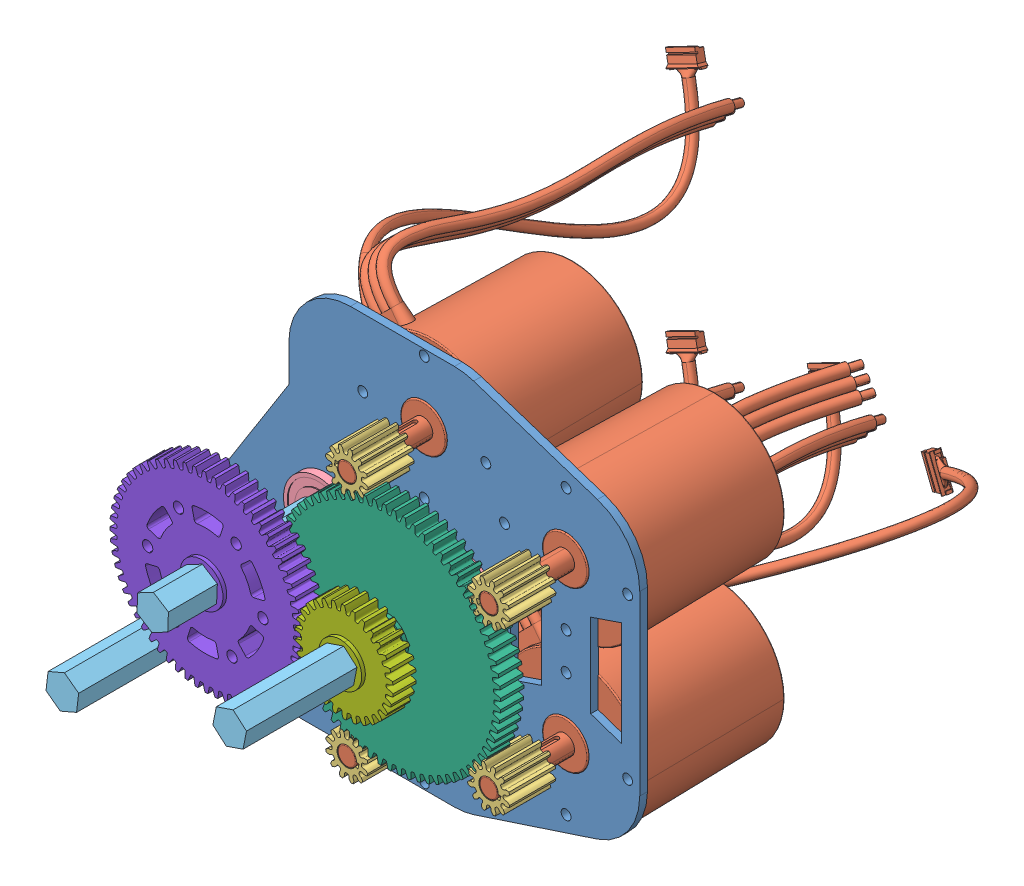
SolidWorks assembly gearbox, configuration Default. Lengths in mm.
Overall size (198.78 175.05 269.62).
20 component instances, 9 part files, 52 mates.
Components (placement in the parent):
- GearboxPlate-1: GearboxPlate [Default] at (89.3688 114.0546 160.1474) size (191.31 157.48 3.17)
- Neo-1: Neo [Default] at (131.3565 147.0746 157.1474) x (0 1 0) z (0 0 1) size (98.87 73.45 204.78)
- Neo-2: Neo [Default] at (72.8588 164.8553 157.1474) size (98.87 73.45 204.78)
- Neo-3: Neo [Default] at (72.8588 63.2539 157.1474) size (98.87 73.45 204.78)
- Neo-4: Neo [Default] at (131.3565 81.0346 157.1474) size (98.87 73.45 204.78)
- 12t_Steel_Spur_Gear_20_DP_CIM_Motor_217-3099.step-1: 12t_Steel_Spur_Gear_20_DP_CIM_Motor_217-3099.step [Default] at (131.3565 147.0746 182.6224) x (-0.324702 0.945816 0) z (0 0 1) size (17.78 17.78 19.05)
- 12t_Steel_Spur_Gear_20_DP_CIM_Motor_217-3099.step-2: 12t_Steel_Spur_Gear_20_DP_CIM_Motor_217-3099.step [Default] at (72.8588 63.2539 182.6224) x (-0.263214 -0.964737 0) z (0 0 1) size (17.78 17.78 19.05)
- 12t_Steel_Spur_Gear_20_DP_CIM_Motor_217-3099.step-3: 12t_Steel_Spur_Gear_20_DP_CIM_Motor_217-3099.step [Default] at (72.8588 164.8553 182.6224) x (0.186373 0.982479 0) z (0 0 1) size (17.78 17.78 19.05)
- 12t_Steel_Spur_Gear_20_DP_CIM_Motor_217-3099.step-4: 12t_Steel_Spur_Gear_20_DP_CIM_Motor_217-3099.step [Default] at (131.3565 81.0346 182.6224) x (-0.249656 -0.968335 0) z (0 0 1) size (17.78 17.78 19.05)
- 0_500_Hex_ID_x_1_125_OD_x_0_313_WD_Flanged_Bearing_v2_217-3875_1-1: 0_500_Hex_ID_x_1_125_OD_x_0_313_WD_Flanged_Bearing_v2_217-3875_1 [Default] at (89.3688 114.0546 163.3224) x (-0.193497 -0.981101 0) z (0.981101 -0.193497 0) size (31.12 7.94 31.12)
- 0_500_Hex_ID_x_1_125_OD_x_0_313_WD_Flanged_Bearing_v2_217-3875_1-2: 0_500_Hex_ID_x_1_125_OD_x_0_313_WD_Flanged_Bearing_v2_217-3875_1 [Default] at (32.2188 114.0546 163.3224) x (-0.885627 -0.464398 0) z (0.464398 -0.885627 0) size (31.12 7.94 31.12)
- 0_500_Hex_ID_x_1_125_OD_x_0_313_WD_Flanged_Bearing_v2_217-3875_1-3: 0_500_Hex_ID_x_1_125_OD_x_0_313_WD_Flanged_Bearing_v2_217-3875_1 [Default] at (-0.286 71.7628 163.3224) x (0.117953 0.993019 0) z (-0.993019 0.117953 0) size (31.12 7.94 31.12)
- hexshaft-1: hexshaft [Default] at (32.229 114.06 129.9849) x (-0.933889 -0.357564 0) z (0 0 1) size (14.56 13.47 101.6)
- hexshaft-4: hexshaft [Default] at (89.3884 114.0507 155.3849) x (-0.306983 -0.951715 0) z (0 0 1) size (14.56 13.47 101.6)
- hexshaft-5: hexshaft [Default] at (-0.2939 71.7812 134.7474) x (0.233353 0.972392 0) z (0 0 1) size (14.56 13.47 101.6)
- 72t_Aluminum_Spur_Gear_20_DP_1_2_Hex_Bore_217-3576.step-1: 72t_Aluminum_Spur_Gear_20_DP_1_2_Hex_Bore_217-3576.step [Default] at (89.4215 114.0218 187.3849) x (0.322977 -0.946407 0) z (0 0 1) size (93.93 93.93 12.65)
- 30t_Steel_Spur_Gear_20_DP_1_2_Hex_Bore_217-5469.step-1: 30t_Steel_Spur_Gear_20_DP_1_2_Hex_Bore_217-5469.step [Default] at (89.3717 114.0316 205.0895) x (0.981101 -0.193497 0) z (0 0 1) size (40.52 40.64 12.6)
- 60t_Aluminum_Spur_Gear_20_DP_1_2_Hex_Bore_VersaKeys_217-2714.step-1: 60t_Aluminum_Spur_Gear_20_DP_1_2_Hex_Bore_VersaKeys_217-2714.step [Default] at (32.1883 113.9956 205.0895) x (0.464398 -0.885627 0) z (0 0 1) size (78.68 78.68 12.65)
- 42t_Aluminum_Spur_Gear_20_DP_1_2_Hex_Bore_217-3216.step-1: 42t_Aluminum_Spur_Gear_20_DP_1_2_Hex_Bore_217-3216.step [Default] at (32.2662 114.0364 149.0349) x (0.464398 -0.885627 0) z (0 0 1) size (55.8 55.88 12.65)
- 42t_Aluminum_Spur_Gear_20_DP_1_2_Hex_Bore_217-3216.step-2: 42t_Aluminum_Spur_Gear_20_DP_1_2_Hex_Bore_217-3216.step [Default] at (-0.3395 71.7202 149.0349) x (-0.394359 0.918956 0) z (0 0 1) size (55.8 55.88 12.65)
Mates (geometry in assembly coordinates):
- Coincident4: coincident anti-aligned: circle of GearboxPlate-1; circle of Neo-2
- Coincident5: coincident anti-aligned: circle of GearboxPlate-1; circle of Neo-3
- Coincident8: coincident aligned: plane of Neo-1 through (131.3565 147.0746 192.1474) normal (0 0 1); plane of 12t_Steel_Spur_Gear_20_DP_CIM_Motor_217-3099.step-1 through (131.3565 147.0746 192.1474) normal (0 0 1)
- Concentric6: concentric aligned: cylinder of Neo-1 through (131.3565 147.0746 238.4611) axis (0 0 -1) radius 4; cylinder of 12t_Steel_Spur_Gear_20_DP_CIM_Motor_217-3099.step-1 through (131.3565 147.0746 192.1474) axis (0 0 -1) radius 4
- Concentric7: concentric aligned: cylinder of Neo-2 through (72.8588 164.8553 238.4611) axis (0 0 -1) radius 4; cylinder of 12t_Steel_Spur_Gear_20_DP_CIM_Motor_217-3099.step-3 through (72.8588 164.8553 192.1474) axis (0 0 -1) radius 4
- Coincident11: coincident aligned: plane of Neo-2 through (72.8588 164.8553 192.1474) normal (0 0 1); plane of 12t_Steel_Spur_Gear_20_DP_CIM_Motor_217-3099.step-3 through (72.8588 164.8553 192.1474) normal (0 0 1)
- Coincident13: coincident aligned: plane of Neo-3 through (72.8588 63.2539 192.1474) normal (0 0 1); plane of 12t_Steel_Spur_Gear_20_DP_CIM_Motor_217-3099.step-2 through (72.8588 63.2539 192.1474) normal (0 0 1)
- Concentric8: concentric aligned: cylinder of Neo-3 through (72.8588 63.2539 238.4611) axis (0 0 -1) radius 4; cylinder of 12t_Steel_Spur_Gear_20_DP_CIM_Motor_217-3099.step-2 through (72.8588 63.2539 192.1474) axis (0 0 -1) radius 4
- Concentric9: concentric aligned: cylinder of Neo-4 through (131.3565 81.0346 238.4611) axis (0 0 -1) radius 4; cylinder of 12t_Steel_Spur_Gear_20_DP_CIM_Motor_217-3099.step-4 through (131.3565 81.0346 192.1474) axis (0 0 -1) radius 4
- Coincident15: coincident aligned: plane of Neo-4 through (131.3565 81.0346 192.1474) normal (0 0 1); plane of 12t_Steel_Spur_Gear_20_DP_CIM_Motor_217-3099.step-4 through (131.3565 81.0346 192.1474) normal (0 0 1)
- Concentric13: concentric anti-aligned: cylinder of GearboxPlate-1 through (89.3688 114.0546 156.9724) axis (0 0 1) radius 14.2875; cylinder of 0_500_Hex_ID_x_1_125_OD_x_0_313_WD_Flanged_Bearing_v2_217-3875_1-1 through (89.3688 114.0546 163.3224) axis (0 0 -1) radius 14.2748
- Coincident21: coincident aligned: plane of GearboxPlate-1 through (89.3688 114.0546 156.9724) normal (0 0 -1); circle of 0_500_Hex_ID_x_1_125_OD_x_0_313_WD_Flanged_Bearing_v2_217-3875_1-1
- Concentric15: concentric anti-aligned: cylinder of GearboxPlate-1 through (32.2188 114.0546 156.9724) axis (0 0 1) radius 14.2875; cylinder of 0_500_Hex_ID_x_1_125_OD_x_0_313_WD_Flanged_Bearing_v2_217-3875_1-2 through (32.2188 114.0546 163.3224) axis (0 0 -1) radius 14.2748
- Coincident22: coincident aligned: plane of GearboxPlate-1 through (89.3688 114.0546 156.9724) normal (0 0 -1); circle of 0_500_Hex_ID_x_1_125_OD_x_0_313_WD_Flanged_Bearing_v2_217-3875_1-2
- Concentric16: concentric anti-aligned: cylinder of GearboxPlate-1 through (-0.286 71.7628 156.9724) axis (0 0 1) radius 14.2875; cylinder of 0_500_Hex_ID_x_1_125_OD_x_0_313_WD_Flanged_Bearing_v2_217-3875_1-3 through (-0.286 71.7628 163.3224) axis (0 0 -1) radius 14.2748
- Coincident23: coincident aligned: plane of GearboxPlate-1 through (89.3688 114.0546 156.9724) normal (0 0 -1); circle of 0_500_Hex_ID_x_1_125_OD_x_0_313_WD_Flanged_Bearing_v2_217-3875_1-3
- Coincident27: coincident anti-aligned: plane of 0_500_Hex_ID_x_1_125_OD_x_0_313_WD_Flanged_Bearing_v2_217-3875_1-2 through (38.7227 117.4651 163.3224) normal (-0.999174 0.040633 0); plane of hexshaft-1 through (38.4248 110.1388 231.5849) normal (0.999174 -0.040633 0)
- Coincident42: coincident anti-aligned: plane of 0_500_Hex_ID_x_1_125_OD_x_0_313_WD_Flanged_Bearing_v2_217-3875_1-1 through (94.8981 109.2214 163.3224) normal (-0.322977 0.946407 0); plane of hexshaft-4 through (87.9696 106.857 256.9849) normal (0.322977 -0.946407 0)
- Coincident43: coincident anti-aligned: line of 0_500_Hex_ID_x_1_125_OD_x_0_313_WD_Flanged_Bearing_v2_217-3875_1-1 through (90.7898 121.2597 155.3849) axis (0.75291 -0.658124 0); line of hexshaft-4 through (96.3278 116.4189 155.3849) axis (-0.75291 0.658124 0)
- Coincident44: coincident anti-aligned: plane of 0_500_Hex_ID_x_1_125_OD_x_0_313_WD_Flanged_Bearing_v2_217-3875_1-3 through (0.5802 79.0555 163.3224) normal (-0.59866 -0.801003 0); plane of hexshaft-5 through (6.4442 74.6728 236.3474) normal (0.59866 0.801003 0)
- Coincident46: coincident anti-aligned: circle of GearboxPlate-1; circle of Neo-1
- Coincident47: coincident anti-aligned: circle of GearboxPlate-1; circle of Neo-4
- Coincident50: coincident anti-aligned: plane of hexshaft-4 through (90.8072 121.2445 256.9849) normal (-0.322977 0.946407 0); plane of 72t_Aluminum_Spur_Gear_20_DP_1_2_Hex_Bore_217-3576.step-1 through (83.8678 118.8763 193.7095) normal (0.322977 -0.946407 0)
- Coincident53: coincident aligned: plane of 12t_Steel_Spur_Gear_20_DP_CIM_Motor_217-3099.step-1 through (131.3565 147.0746 192.1474) normal (0 0 1); plane of 72t_Aluminum_Spur_Gear_20_DP_1_2_Hex_Bore_217-3576.step-1 through (89.4215 114.0218 192.1474) normal (0 0 1)
- GearMate1: gear = 93.98 : 17.78 mm: cylinder of 12t_Steel_Spur_Gear_20_DP_CIM_Motor_217-3099.step-1 through (131.3565 147.0746 182.6224) axis (0 0 1) radius 8.89; cylinder of 72t_Aluminum_Spur_Gear_20_DP_1_2_Hex_Bore_217-3576.step-1 through (89.4215 114.0218 187.3849) axis (0 0 1) radius 46.99
- Coincident55: coincident anti-aligned: plane of hexshaft-4 through (83.8678 118.8763 256.9849) normal (-0.981101 0.193497 0); plane of 72t_Aluminum_Spur_Gear_20_DP_1_2_Hex_Bore_217-3576.step-1 through (82.4405 111.6394 193.7095) normal (0.981101 -0.193497 0)
- GearMate2: gear = 17.78 : 93.98 mm: cylinder of 72t_Aluminum_Spur_Gear_20_DP_1_2_Hex_Bore_217-3576.step-1 through (89.4215 114.0218 187.3849) axis (0 0 1) radius 46.99; cylinder of 12t_Steel_Spur_Gear_20_DP_CIM_Motor_217-3099.step-3 through (72.8588 164.8553 182.6224) axis (0 0 1) radius 8.89
- GearMate3: gear = 17.78 : 93.98 mm: cylinder of 72t_Aluminum_Spur_Gear_20_DP_1_2_Hex_Bore_217-3576.step-1 through (89.4215 114.0218 187.3849) axis (0 0 1) radius 46.99; cylinder of 12t_Steel_Spur_Gear_20_DP_CIM_Motor_217-3099.step-2 through (72.8588 63.2539 182.6224) axis (0 0 1) radius 8.89
- GearMate4: gear = 93.98 : 17.78 mm: cylinder of 12t_Steel_Spur_Gear_20_DP_CIM_Motor_217-3099.step-4 through (131.3565 81.0346 182.6224) axis (0 0 1) radius 8.89; cylinder of 72t_Aluminum_Spur_Gear_20_DP_1_2_Hex_Bore_217-3576.step-1 through (89.4215 114.0218 187.3849) axis (0 0 1) radius 46.99
- Coincident59: coincident anti-aligned: plane of hexshaft-4 through (90.8072 121.2445 256.9849) normal (-0.322977 0.946407 0); plane of 30t_Steel_Spur_Gear_20_DP_1_2_Hex_Bore_217-5469.step-1 through (83.84 118.8669 211.3895) normal (0.322977 -0.946407 0)
- Coincident60: coincident anti-aligned: plane of hexshaft-1 through (32.5269 121.3863 231.5849) normal (-0.464398 0.885627 0); plane of 60t_Aluminum_Spur_Gear_20_DP_1_2_Hex_Bore_VersaKeys_217-2714.step-1 through (25.9553 117.9403 211.4141) normal (0.464398 -0.885627 0)
- Coincident61: coincident aligned: plane of 30t_Steel_Spur_Gear_20_DP_1_2_Hex_Bore_217-5469.step-1 through (89.3717 114.0316 209.852) normal (0 0 1); plane of 60t_Aluminum_Spur_Gear_20_DP_1_2_Hex_Bore_VersaKeys_217-2714.step-1 through (32.1883 113.9956 209.852) normal (0 0 1)
- Coincident62: coincident anti-aligned: plane of hexshaft-1 through (38.4248 110.1388 231.5849) normal (0.999174 -0.040633 0); plane of 60t_Aluminum_Spur_Gear_20_DP_1_2_Hex_Bore_VersaKeys_217-2714.step-1 through (38.7209 117.4211 211.4141) normal (-0.999174 0.040633 0)
- GearMate5: gear = 78.74 : 40.64 mm: cylinder of 30t_Steel_Spur_Gear_20_DP_1_2_Hex_Bore_217-5469.step-1 through (89.3717 114.0316 205.0895) axis (0 0 1) radius 20.32; cylinder of 60t_Aluminum_Spur_Gear_20_DP_1_2_Hex_Bore_VersaKeys_217-2714.step-1 through (32.1883 113.9956 205.0895) axis (0 0 1) radius 39.37
- Distance1: distance = 5.08 mm anti-aligned: plane of 30t_Steel_Spur_Gear_20_DP_1_2_Hex_Bore_217-5469.step-1 through (89.3717 114.0316 198.7895) normal (0 0 -1); plane of 72t_Aluminum_Spur_Gear_20_DP_1_2_Hex_Bore_217-3576.step-1 through (89.4215 114.0218 193.7095) normal (0 0 1)
- Distance3: distance = 25.4 mm: line of hexshaft-1 through (38.4248 110.1388 129.9849) axis (0.040633 0.999174 0); line of 0_500_Hex_ID_x_1_125_OD_x_0_313_WD_Flanged_Bearing_v2_217-3875_1-2 through (38.7227 117.4651 155.3849) axis (-0.040633 -0.999174 0)
- Parallel5: parallel anti-aligned: plane of 0_500_Hex_ID_x_1_125_OD_x_0_313_WD_Flanged_Bearing_v2_217-3875_1-3 through (-1.1523 64.4702 163.3224) normal (0.59866 0.801003 0); plane of hexshaft-5 through (-7.032 68.8896 236.3474) normal (-0.59866 -0.801003 0)
- Coincident72: coincident: line of 0_500_Hex_ID_x_1_125_OD_x_0_313_WD_Flanged_Bearing_v2_217-3875_1-3 through (-7.0348 68.8667 163.3224) axis (0.117953 0.993019 0); plane of hexshaft-5 through (-6.1672 76.1708 236.3474) normal (-0.993019 0.117953 0)
- Distance7: distance = 76.2 mm aligned: plane of hexshaft-5 through (-0.2939 71.7812 236.3474) normal (0 0 1); plane of GearboxPlate-1 through (89.3688 114.0546 160.1474) normal (0 0 1)
- Coincident82: coincident: line of 0_500_Hex_ID_x_1_125_OD_x_0_313_WD_Flanged_Bearing_v2_217-3875_1-2 through (32.5172 121.3924 163.3224) axis (0.844994 -0.534776 0); plane of hexshaft-1 through (38.7227 117.4651 231.5849) normal (0.534776 0.844994 0)
- Coincident83: coincident: plane of hexshaft-4 through (94.909 109.2251 256.9849) normal (0.981101 -0.193497 0); line of 30t_Steel_Spur_Gear_20_DP_1_2_Hex_Bore_217-5469.step-1 through (96.3249 116.4045 211.3895) axis (-0.193497 -0.981101 0)
- Coincident84: coincident: plane of hexshaft-1 through (32.5269 121.3863 231.5849) normal (-0.464398 0.885627 0); line of 42t_Aluminum_Spur_Gear_20_DP_1_2_Hex_Bore_217-3216.step-1 through (32.5659 121.4067 142.7103) axis (-0.885627 -0.464398 0)
- Coincident87: coincident: plane of hexshaft-1 through (26.0332 117.9811 231.5849) normal (-0.999174 0.040633 0); line of 42t_Aluminum_Spur_Gear_20_DP_1_2_Hex_Bore_217-3216.step-1 through (26.0332 117.9811 142.7103) axis (-0.040633 -0.999174 0)
- Distance11: distance = 12.7 mm aligned: plane of 42t_Aluminum_Spur_Gear_20_DP_1_2_Hex_Bore_217-3216.step-1 through (32.2662 114.0364 144.2724) normal (0 0 -1); plane of GearboxPlate-1 through (89.3688 114.0546 156.9724) normal (0 0 -1)
- Coincident89: coincident anti-aligned: plane of hexshaft-5 through (0.5709 79.0624 236.3474) normal (-0.394359 0.918956 0); plane of 42t_Aluminum_Spur_Gear_20_DP_1_2_Hex_Bore_217-3216.step-2 through (0.5305 79.045 142.7103) normal (0.394359 -0.918956 0)
- Coincident90: coincident: line of hexshaft-5 through (5.5793 67.3916 134.7474) axis (0.117953 0.993019 0); plane of 42t_Aluminum_Spur_Gear_20_DP_1_2_Hex_Bore_217-3216.step-2 through (5.5689 67.3043 142.7103) normal (-0.993019 0.117953 0)
- Coincident91: coincident aligned: plane of 42t_Aluminum_Spur_Gear_20_DP_1_2_Hex_Bore_217-3216.step-1 through (32.2662 114.0364 144.2724) normal (0 0 -1); plane of 42t_Aluminum_Spur_Gear_20_DP_1_2_Hex_Bore_217-3216.step-2 through (-0.3395 71.7202 144.2724) normal (0 0 -1)
- GearMate7: gear = 55.88 : 55.88 mm: cylinder of 42t_Aluminum_Spur_Gear_20_DP_1_2_Hex_Bore_217-3216.step-2 through (-0.3395 71.7202 153.7974) axis (0 0 -1) radius 27.94; cylinder of 42t_Aluminum_Spur_Gear_20_DP_1_2_Hex_Bore_217-3216.step-1 through (32.2662 114.0364 153.7974) axis (0 0 -1) radius 27.94
- Concentric17: concentric aligned: circle of GearboxPlate-1; circle of Neo-2
- Concentric18: concentric aligned: circle of GearboxPlate-1; circle of Neo-1
- Concentric19: concentric aligned: circle of GearboxPlate-1; circle of Neo-4
- Concentric20: concentric anti-aligned: circle of GearboxPlate-1; circle of Neo-3
